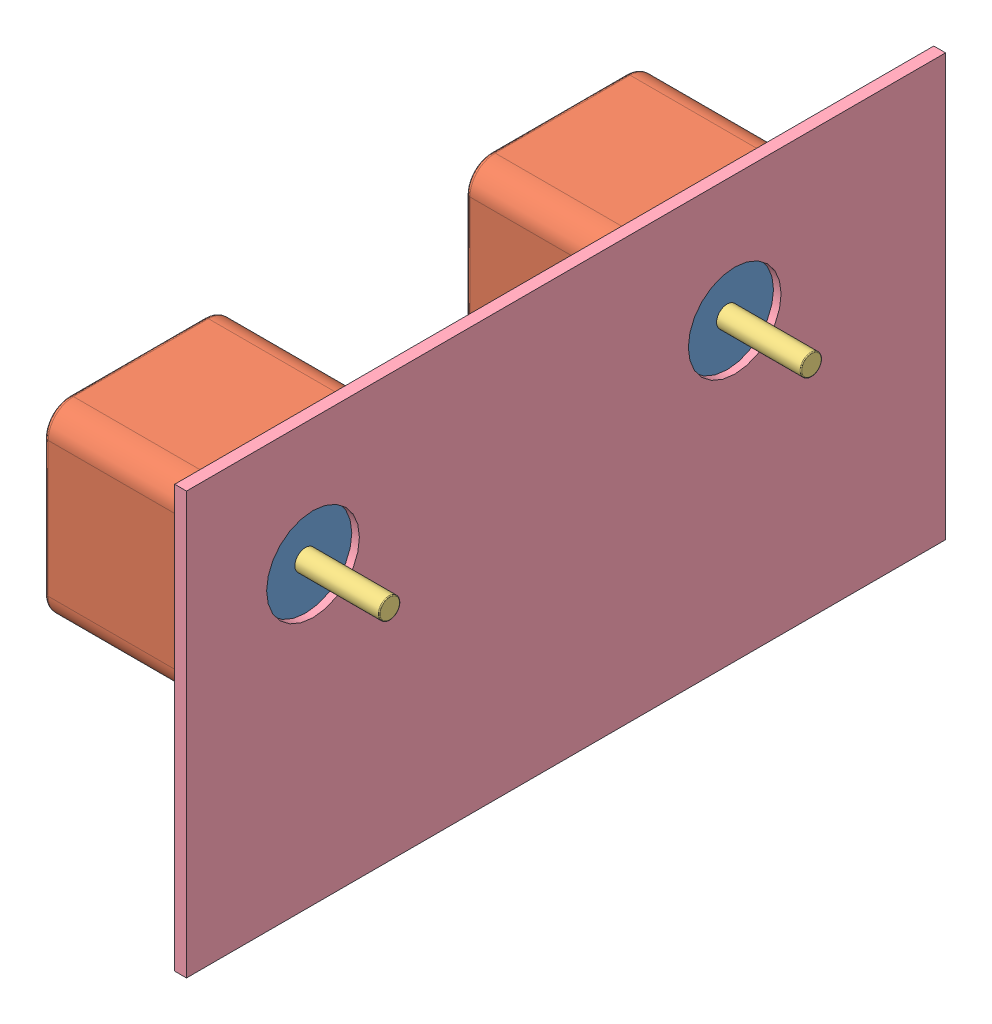
SolidWorks assembly MainAssembly, configuration Default. Lengths in mm.
Overall size (60 100 180).
9 component instances, 4 part files, 4 mates.
Components (placement in the parent):
- MotorAssem-1: MotorAssem [Default] at (5.3203 73.6567 68.2493) size (60 44 44)
  - Nema17_StepperMotorCap-1: Nema17_StepperMotorCap [Default] at origin size (7 44 44)
  - Nema17_StepperMotorCase-1: Nema17_StepperMotorCase [Default] at (-33 0 0) size (33 44 44)
  - StepperMotorShaft-1: StepperMotorShaft [Default] at (-33 0 0) x (0 0 -1) z (1 0 0) size (5 5 60)
- MotorAssem-2: MotorAssem [Default] at (5.3203 73.6567 -31.7507) size (60 44 44)
  - Nema17_StepperMotorCap-1: Nema17_StepperMotorCap [Default] at origin size (7 44 44)
  - Nema17_StepperMotorCase-1: Nema17_StepperMotorCase [Default] at (-33 0 0) size (33 44 44)
  - StepperMotorShaft-1: StepperMotorShaft [Default] at (-33 0 0) x (0 0 -1) z (1 0 0) size (5 5 60)
- BodyMidRightSLDPRT-1: BodyMidRightSLDPRT [Default] at (11.3203 3.6567 98.2493) x (0 0 -1) z (1 0 0) size (180 100 2.8)
Mates (geometry in assembly coordinates):
- Coincident7: coincident anti-aligned: plane of MotorAssem-1/Nema17_StepperMotorCap-1 through (11.3203 73.6567 68.2473) normal (1 0 0); plane of Part2^MainAssembly-1 through (11.3203 3.6567 98.2493) normal (-1 0 0)
- Concentric1: concentric aligned: cylinder of MotorAssem-1/Nema17_StepperMotorCap-1 through (12.3203 73.6567 68.2493) axis (-1 0 0) radius 11; cylinder of Part2^MainAssembly-1 through (14.1203 73.6567 68.2493) axis (-1 0 0) radius 11
- Concentric2: concentric aligned: cylinder of MotorAssem-2/Nema17_StepperMotorCap-1 through (12.3203 73.6567 -31.7507) axis (-1 0 0) radius 11; cylinder of Part2^MainAssembly-1 through (14.1203 73.6567 -31.7507) axis (-1 0 0) radius 11
- Coincident8: coincident anti-aligned: plane of MotorAssem-2/Nema17_StepperMotorCap-1 through (11.3203 73.6567 -31.7527) normal (1 0 0); plane of Part2^MainAssembly-1 through (11.3203 3.6567 98.2493) normal (-1 0 0)
